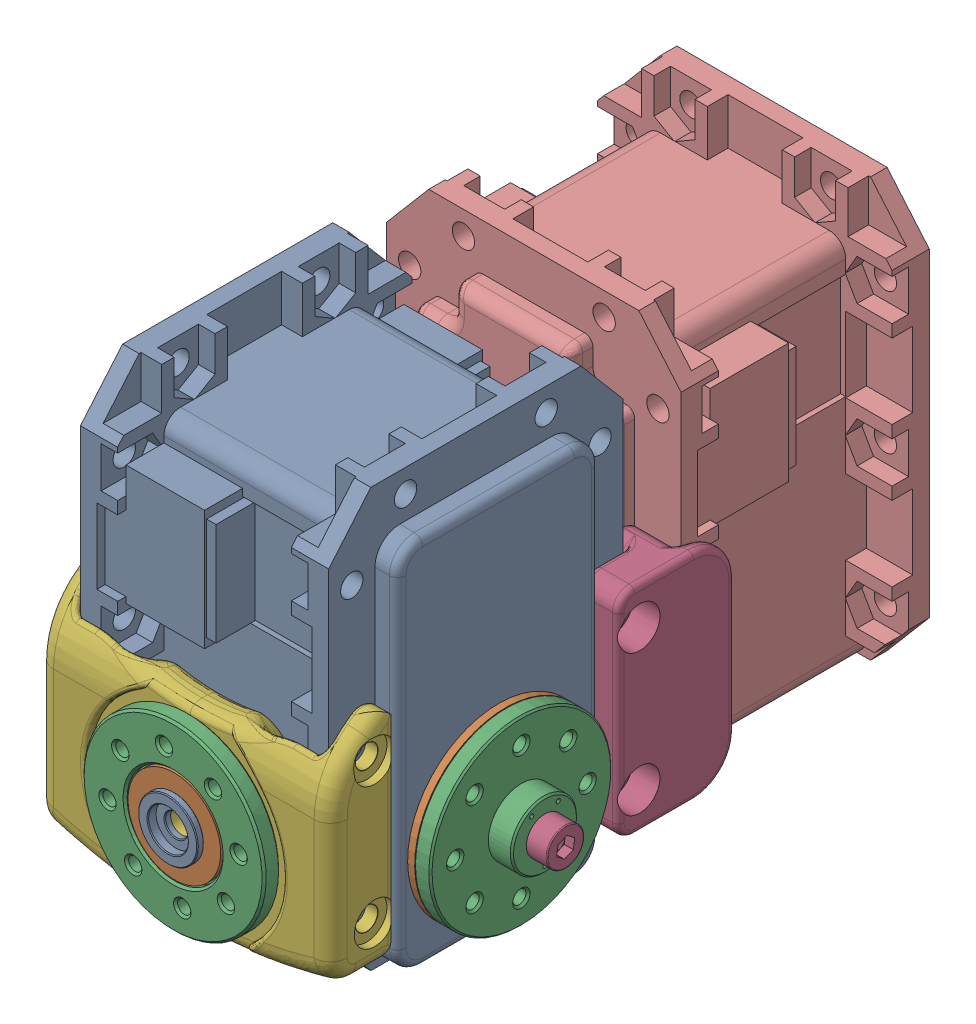
SolidWorks assembly double_rotation(full_MX28), configuration Default. Lengths in mm.
Overall size (48.5 54.13 85.1).
21 component instances, 12 part files, 0 mates.
Components (placement in the parent):
- MX-28(U)-6-1: MX-28(U)-6 [Default] x (0 0 1) z (1 0 0) size (35.6 54.13 48.5)
  - dynamixel_x28series(U)-1: dynamixel_x28series(U) [Default] at origin size (35.6 50.71 41.85)
  - trust_washer(U)-1: trust_washer(U) [Default] at (0 0 18.6) x (-0.666375 -0.745617 0) z (0.745617 -0.666375 0) size (22 0.85 22)
  - HN07-N101(U)-1: HN07-N101(U) [Default] at (0 0 18.5) x (1 0 0) z (0 -1 0) size (22 5.85 22)
  - WB_M2.5x8-1: WB_M2.5x8 [Default] at (0 0 25.85) x (0 0 -1) z (-0.991137 0.132843 0) size (10.5 4.5 4.5)
  - WB_M2.5x8-2: WB_M2.5x8 [Default] at (0 0 -22.65) x (0 0 1) z (-0.936501 0.350665 0) size (10.5 4.5 4.5)
  - RX28-CAP-1: RX28-CAP [Default] at (0 0 -20.35) x (-0.995735 -0.092256 0) z (0 0 -1) size (7.2 7.2 1.8)
  - MF106ZZ-1: MF106ZZ [Default] at (0 0 -20.35) x (0.888333 -0.4592 0) z (-0.4592 -0.888333 0) size (11.2 3 11.2)
  - HN07-i101-1: HN07-i101 [Default] at (0 0 -20.5) x (1 0 0) z (0 1 0) size (22 3.05 22)
- MX-28(T)-3-1: MX-28(T)-3 [Default] at (0 0 -37) x (1 0 0) z (0 0 -1) size (35.6 54.13 45.1)
  - WB_M2.5x8-1: WB_M2.5x8 [Default] at (0 0 25.85) x (0 0 -1) z (-0.991137 0.132843 0) size (10.5 4.5 4.5)
  - dynamixel_x28series(Défaut)-1: dynamixel_x28series(Défaut) [Default] at origin size (35.6 50.71 41.85)
  - trust_washer(Défaut)-1: trust_washer(Défaut) [Default] at (0 0 18.6) x (-0.666375 -0.745617 0) z (0.745617 -0.666375 0) size (22 0.85 22)
  - HN07-N101(Défaut)-1: HN07-N101(Défaut) [Default] at (0 0 18.5) x (1 0 0) z (0 -1 0) size (22 5.85 22)
- i101_Set(FR07)-1: i101_Set(FR07) [Default] at (0 0 21.6) x (-0.798096 0.60253 0) z (0 0 1) size (22 22 3.8)
  - RX28-CAP-1: RX28-CAP [Default] at (0 0 -0.15) size (7.2 7.2 1.8)
  - MF106ZZ-1: MF106ZZ [Default] at (0 0 -0.15) x (-0.837169 0.546944 0) z (-0.546944 -0.837169 0) size (11.2 3 11.2)
  - HN07-i101-1: HN07-i101 [Default] x (1 0 0) z (0 -1 0) size (22 3.05 22)
- double_rotation_link(double_MX28)-1: double_rotation_link(double_MX28) [Default] at (0 -0.5 0) size (7.4 26.51 14.1)
- double_rotation_link(double_MX28)-2: double_rotation_link(double_MX28) [Default] at (0 8.5 0) x (-1 0 0) z (0 0 1) size (7.4 26.51 14.1)
- i101-Set_to_MX_link(MX28_compatible)-1: i101-Set_to_MX_link(MX28_compatible) [Default] x (0 0 -1) z (1 0 0) size (8.29 28.53 35.81)
